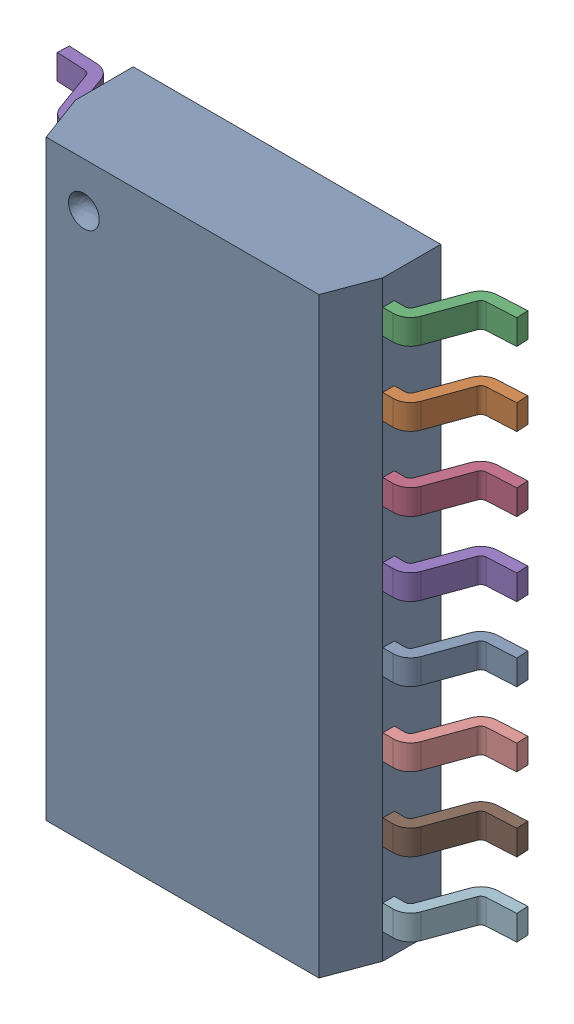
SolidWorks assembly SOP-16, configuration ﾃﾞﾌｫﾙﾄ. Lengths in mm.
Overall size (7.92 10.2 2.07).
30 component instances, 2 part files, 0 mates.
Components (placement in the parent):
- User Library-SOP16_208mil (5.3mm)-1: User Library-SOP16_208mil (5.3mm) [ﾃﾞﾌｫﾙﾄ] x (-1 0 0) z (0 0 1) size (7.92 10.2 2.07)
  - SOP16 Body-1: SOP16 Body [ﾃﾞﾌｫﾙﾄ] at origin size (5.3 10.2 1.87)
  - Foot SOP16-1: Foot SOP16 [ﾃﾞﾌｫﾙﾄ] at (3.95 -0.85 -0.1979) x (-1 0 0) z (0 0 1) size (1.31 0.43 1.2)
  - Foot SOP16-2: Foot SOP16 [ﾃﾞﾌｫﾙﾄ] at (3.95 -2.12 -0.1979) x (-1 0 0) z (0 0 1) size (1.31 0.43 1.2)
  - Foot SOP16-3: Foot SOP16 [ﾃﾞﾌｫﾙﾄ] at (3.95 -3.39 -0.1979) x (-1 0 0) z (0 0 1) size (1.31 0.43 1.2)
  - Foot SOP16-4: Foot SOP16 [ﾃﾞﾌｫﾙﾄ] at (3.95 -4.66 -0.1979) x (-1 0 0) z (0 0 1) size (1.31 0.43 1.2)
  - Foot SOP16-5: Foot SOP16 [ﾃﾞﾌｫﾙﾄ] at (3.95 0.42 -0.1979) x (-1 0 0) z (0 0 1) size (1.31 0.43 1.2)
  - Foot SOP16-6: Foot SOP16 [ﾃﾞﾌｫﾙﾄ] at (3.95 -0.85 -0.1979) x (-1 0 0) z (0 0 1) size (1.31 0.43 1.2)
  - Foot SOP16-7: Foot SOP16 [ﾃﾞﾌｫﾙﾄ] at (3.95 -2.12 -0.1979) x (-1 0 0) z (0 0 1) size (1.31 0.43 1.2)
  - Foot SOP16-8: Foot SOP16 [ﾃﾞﾌｫﾙﾄ] at (3.95 -3.39 -0.1979) x (-1 0 0) z (0 0 1) size (1.31 0.43 1.2)
  - Foot SOP16-9: Foot SOP16 [ﾃﾞﾌｫﾙﾄ] at (3.95 1.69 -0.1979) x (-1 0 0) z (0 0 1) size (1.31 0.43 1.2)
  - Foot SOP16-10: Foot SOP16 [ﾃﾞﾌｫﾙﾄ] at (3.95 0.42 -0.1979) x (-1 0 0) z (0 0 1) size (1.31 0.43 1.2)
  - Foot SOP16-11: Foot SOP16 [ﾃﾞﾌｫﾙﾄ] at (3.95 -0.85 -0.1979) x (-1 0 0) z (0 0 1) size (1.31 0.43 1.2)
  - Foot SOP16-12: Foot SOP16 [ﾃﾞﾌｫﾙﾄ] at (3.95 -2.12 -0.1979) x (-1 0 0) z (0 0 1) size (1.31 0.43 1.2)
  - Foot SOP16-13: Foot SOP16 [ﾃﾞﾌｫﾙﾄ] at (3.95 2.96 -0.1979) x (-1 0 0) z (0 0 1) size (1.31 0.43 1.2)
  - Foot SOP16-14: Foot SOP16 [ﾃﾞﾌｫﾙﾄ] at (3.95 1.69 -0.1979) x (-1 0 0) z (0 0 1) size (1.31 0.43 1.2)
  - Foot SOP16-15: Foot SOP16 [ﾃﾞﾌｫﾙﾄ] at (3.95 0.42 -0.1979) x (-1 0 0) z (0 0 1) size (1.31 0.43 1.2)
  - Foot SOP16-16: Foot SOP16 [ﾃﾞﾌｫﾙﾄ] at (3.95 -0.85 -0.1979) x (-1 0 0) z (0 0 1) size (1.31 0.43 1.2)
  - Foot SOP16-17: Foot SOP16 [ﾃﾞﾌｫﾙﾄ] at (3.95 4.23 -0.1979) x (-1 0 0) z (0 0 1) size (1.31 0.43 1.2)
  - Foot SOP16-18: Foot SOP16 [ﾃﾞﾌｫﾙﾄ] at (3.95 2.96 -0.1979) x (-1 0 0) z (0 0 1) size (1.31 0.43 1.2)
  - Foot SOP16-19: Foot SOP16 [ﾃﾞﾌｫﾙﾄ] at (3.95 1.69 -0.1979) x (-1 0 0) z (0 0 1) size (1.31 0.43 1.2)
  - Foot SOP16-20: Foot SOP16 [ﾃﾞﾌｫﾙﾄ] at (3.95 0.42 -0.1979) x (-1 0 0) z (0 0 1) size (1.31 0.43 1.2)
  - Foot SOP16-21: Foot SOP16 [ﾃﾞﾌｫﾙﾄ] at (-3.95 2.12 -0.1979) size (1.31 0.43 1.2)
  - Foot SOP16-22: Foot SOP16 [ﾃﾞﾌｫﾙﾄ] at (-3.95 3.39 -0.1979) size (1.31 0.43 1.2)
  - Foot SOP16-23: Foot SOP16 [ﾃﾞﾌｫﾙﾄ] at (-3.95 4.66 -0.1979) size (1.31 0.43 1.2)
  - Foot SOP16-24: Foot SOP16 [ﾃﾞﾌｫﾙﾄ] at (-3.95 0.85 -0.1979) size (1.31 0.43 1.2)
  - Foot SOP16-25: Foot SOP16 [ﾃﾞﾌｫﾙﾄ] at (-3.95 -2.96 -0.1979) size (1.31 0.43 1.2)
  - Foot SOP16-26: Foot SOP16 [ﾃﾞﾌｫﾙﾄ] at (-3.95 -4.23 -0.1979) size (1.31 0.43 1.2)
  - Foot SOP16-27: Foot SOP16 [ﾃﾞﾌｫﾙﾄ] at (-3.95 -1.69 -0.1979) size (1.31 0.43 1.2)
  - Foot SOP16-28: Foot SOP16 [ﾃﾞﾌｫﾙﾄ] at (-3.95 -0.42 -0.1979) size (1.31 0.43 1.2)
